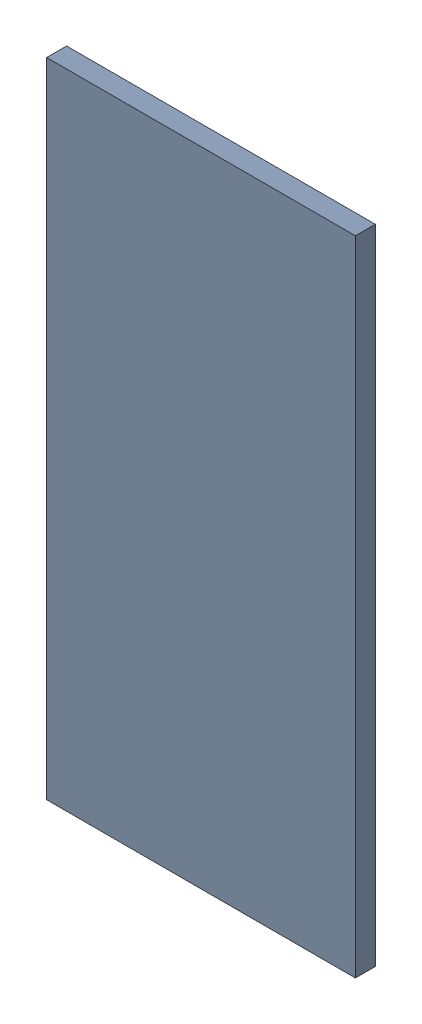
SolidWorks assembly Pad ADXL345-3(21.4mm,58.097mm) on Top Layer, configuration Predeterminado. Lengths in mm.
Overall size (0.55 1.15 0.04).
2 component instances, 1 part files, 0 mates.
Components (placement in the parent):
- Pad ADXL345-3(21.4mm,58.097mm) on Top Layer-1-1: Pad ADXL345-3(21.4mm,58.097mm) on Top Layer-1 [Predeterminado] at (-68.317 -44.187 -0.0457) size (0.55 1.15 0.04)
  - Pad ADXL345-3(21.4mm,58.097mm) on Top Layer-Part-1-1: Pad ADXL345-3(21.4mm,58.097mm) on Top Layer-Part-1 [Predeterminado] at origin size (0.55 1.15 0.04)
